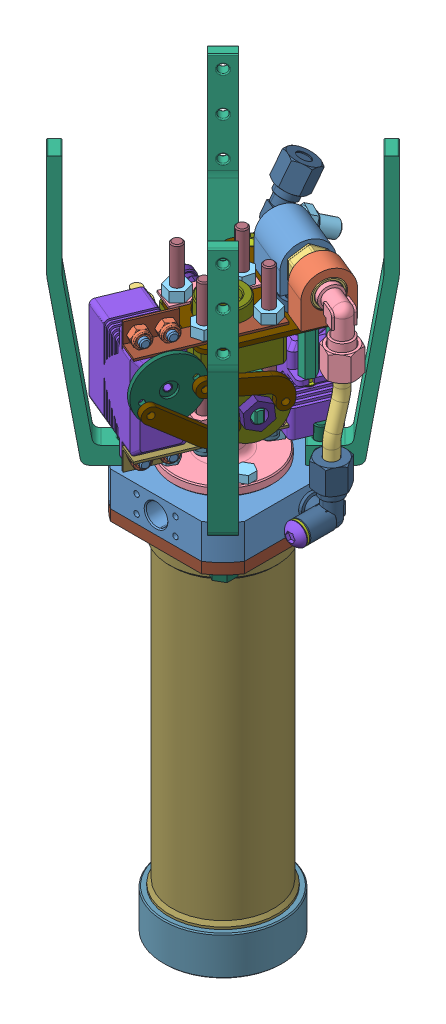
SolidWorks assembly Engine_new, configuration Standard. Lengths in mm.
Overall size (102.61 315 114.21).
81 component instances, 42 part files, 150 mates.
Components (placement in the parent):
- P52_Engine_Head-1: P52_Engine_Head [Default] at origin size (62 16 62)
- P53_G-1-8_M6_Elbow-1: P53_G-1-8_M6_Elbow [Default] at (-24 8 0) x (0 1 0) z (0 0 1) size (31.91 21 12)
- P8_Pressure_Sensor-1: P8_Pressure_Sensor [Default] at (-40 34.9 0) x (0 1 0) z (-0.866025 0 0.5) size (35.2 13.2 14.52)
- P37_Injector_Lower_Ox_Valve_Flange-1: P37_Injector_Lower_Ox_Valve_Flange [Default] at (0 45 0) x (0.92388 0 0.382683) z (0.382683 0 -0.92388) size (46 45 46)
- Fastener_HexHead_M4_10-12: Fastener_HexHead_M4_10 [Default] at (-7.271 23.5 17.5537) x (0.5 0 -0.866025) z (-0.866025 0 -0.5) size (8.08 13.5 7)
- P36_Ox_Valve_Body-1: P36_Ox_Valve_Body [Default] at (0 45.4 0) x (-0.382683 0 0.92388) z (-0.92388 0 -0.382683) size (33 15.39 48.3)
- USIT_M6-1: USIT_M6 [Default] at (-16.1679 40 -6.697) x (-0.215584 -0.82622 0.520466) z (-0.316181 0.563348 0.763328) size (10 1 10)
- Fastener_ButtonHead_M6_5-3: Fastener_ButtonHead_M6_5 [Default] at (-16.1679 40 -6.697) x (0.382683 0 -0.92388) z (0 1 0) size (10 8.13 10)
- P62_Venturi-1: P62_Venturi [Default] at (21.2526 8 -9) x (1 0 0) z (0 0.588472 0.808518) size (10 7.9 7.9)
- P45_6mm_G1-8_Elbow_with_Fill_Nipple-1: P45_6mm_G1-8_Elbow_with_Fill_Nipple [Default] at (36.8359 25.5 -9) x (0 -1 0) z (0 0 1) size (29.13 25.94 23.27)
- Fastener_HexHead_M4_10-13: Fastener_HexHead_M4_10 [Default] at (-17.5537 23.5 -7.271) x (0.866025 0 0.5) z (0.5 0 -0.866025) size (8.08 13.5 7)
- Fastener_HexHead_M4_10-14: Fastener_HexHead_M4_10 [Default] at (7.271 23.5 -17.5537) x (-0.5 0 0.866025) z (0.866025 0 0.5) size (8.08 13.5 7)
- Fastener_HexHead_M4_10-15: Fastener_HexHead_M4_10 [Default] at (17.5537 23.5 7.271) x (-0.866025 0 -0.5) z (-0.5 0 0.866025) size (8.08 13.5 7)
- USIT_M6-2: USIT_M6 [Default] at (40.6506 8.602 5.5) x (1 0 0) z (0 -1 0) size (10 1 10)
- Fastener_ButtonHead_M6_5-2: Fastener_ButtonHead_M6_5 [Default] at (40.6506 8.602 6.5) x (0.866025 -0.5 0) z (-0.5 -0.866025 0) size (10 8.13 10)
- P76ChamberCasing_Flange-1: P76ChamberCasing_Flange [Default] at (0 -5 0) size (62 5 62)
- P74_ChamberCasing_Tube-1: P74_ChamberCasing_Tube [Default] at (0 -170 0) x (0.700468 0 0.713684) z (-0.713684 0 0.700468) size (50 165 50)
- P77_Chamber_Liner-1: P77_Chamber_Liner [Default] at (0 -175 0) x (0.907131 0 0.420848) z (-0.420848 0 0.907131) size (44 170 44)
- P75_ChamberCasing_Retainer-1: P75_ChamberCasing_Retainer [Default] at (0 -174 0) x (-0.824424 0 -0.565973) z (0.565973 0 -0.824424) size (55 18 55)
- Fastener_HexHead_M5_35-1: Fastener_HexHead_M5_35 [Default] at (22.6274 -8.5 -22.6274) size (10.16 38.5 8.8)
- Fastener_HexHead_M5_35-2: Fastener_HexHead_M5_35 [Default] at (22.6274 -8.5 22.6274) x (0 0 1) z (-1 0 0) size (10.16 38.5 8.8)
- Fastener_HexHead_M5_35-3: Fastener_HexHead_M5_35 [Default] at (-22.6274 -8.5 22.6274) x (-1 0 0) z (0 0 -1) size (10.16 38.5 8.8)
- Fastener_HexHead_M5_35-4: Fastener_HexHead_M5_35 [Default] at (-22.6274 -8.5 -22.6274) x (0 0 -1) z (1 0 0) size (10.16 38.5 8.8)
- P40_Upper_Ox_Valve_Flange-1: P40_Upper_Ox_Valve_Flange [Default] at (0 60.1 0) x (0.382683 0 -0.92388) z (0.92388 0 0.382683) size (33 21.2 33)
- P73_Fill_Nipple_8mm-1: P73_Fill_Nipple_8mm [Default] at (-33.7216 66.7 -13.9679) x (-0.92388 0 -0.382683) z (-0.285627 -0.665521 0.689564) size (28 12 13.86)
- P28_Fuel_Valve_Plate-1: P28_Fuel_Valve_Plate [Default] at (0 73.3 0) x (-0.382683 0 0.92388) z (-0.92388 0 -0.382683) size (54.05 2 56)
- P46_Fuel_Valve_Holder_Large-1: P46_Fuel_Valve_Holder_Large [Standard] at (-5.7135 87.8 -33.2427) x (0.92388 0 0.382683) z (-0.382683 0 0.92388) size (22 22.5 20)
- P47_Fuel_Valve_Holder_Small-1: P47_Fuel_Valve_Holder_Small [Standard] at (31.2417 87.8 -17.9354) x (-0.92388 0 -0.382683) z (0.382683 0 -0.92388) size (11 22.5 20)
- P43_Fuel_Valve-1: P43_Fuel_Valve [Default] at (9.4425 86.9775 -26.9649) x (0.92388 0 0.382683) z (0.382683 0 -0.92388) size (36.01 20.82 21.82)
- P44_6mm_G1-8_Elbow_Comp_Ring_Fitting-1: P44_6mm_G1-8_Elbow_Comp_Ring_Fitting [Default] at (37.3239 70.3 -15.4161) x (0 1 0) z (0.382683 0 -0.92388) size (29.13 25.94 17.54)
- P45_6mm_G1-8_Elbow_with_Fill_Nipple-2: P45_6mm_G1-8_Elbow_with_Fill_Nipple [Default] at (-5.1644 103.5289 -41.3189) x (-0.167757 -0.898794 0.405002) z (0.343954 -0.438371 -0.830377) size (29.13 25.94 23.27)
- P72_Fill_Port_Fuel-1: P72_Fill_Port_Fuel [Default] at (-8.2559 84.1765 -43.8235) x (-0.223289 0.820781 -0.525795) z (-0.912051 -0.366263 -0.184427) size (12.7 23.5 11)
- Fastener_HexSpacer_M4_20-5: Fastener_HexSpacer_M4_20 [Default] at (23.785 53.3 -15.6121) x (0.999375 0 0.03534) z (-0.03534 0 0.999375) size (6.93 20 6)
- Fastener_HexSpacer_M4_20-6: Fastener_HexSpacer_M4_20 [Default] at (27.6119 53.3 -24.8509) size (6.93 20 6)
- Fastener_HexSpacer_M4_20-7: Fastener_HexSpacer_M4_20 [Default] at (-16.7344 53.3 -43.2197) size (6.93 20 6)
- Fastener_HexSpacer_M4_20-8: Fastener_HexSpacer_M4_20 [Default] at (-20.5612 53.3 -33.9809) size (6.93 20 6)
- Fastener_ButtonHead_M4_5-17: Fastener_ButtonHead_M4_5 [Default] at (0.8193 73.3 -35.9487) x (-0.837169 0 -0.546944) z (-0.546944 0 0.837169) size (7 6.91 7)
- Fastener_ButtonHead_M4_5-14: Fastener_ButtonHead_M4_5 [Default] at (-3.0075 73.3 -26.7099) x (1 0 0) z (0 0 -1) size (7 6.91 7)
- Fastener_ButtonHead_M4_5-15: Fastener_ButtonHead_M4_5 [Default] at (-16.7344 75.3 -43.2197) size (7 6.91 7)
- Fastener_ButtonHead_M4_5-13: Fastener_ButtonHead_M4_5 [Default] at (-20.5612 75.3 -33.9809) size (7 6.91 7)
- P41_Servo-1: P41_Servo [Default] at (3.5252 51.05 -29.4159) x (-0.92388 0 -0.382683) z (0 1 0) size (54 20.2 42.6)
- P42Sub_ServoPlate20mm-1: P42Sub_ServoPlate20mm [Standard] at (12.7641 69.25 -25.5891) x (-0.058101 0 0.998311) z (0 -1 0) size (20 20 5)
- P42Sub_ServoValveConnector-1: P42Sub_ServoValveConnector [Standard] at (12.7641 69.25 -25.5891) x (0.664829 0 0.746996) z (-0.746996 0 0.664829) size (20 8 20)
- Fastener_ButtonHead_M4_5-19: Fastener_ButtonHead_M4_5 [Default] at (27.6119 51.05 -24.8509) x (-0.400507 0 0.916294) z (0.916294 0 0.400507) size (7 6.91 7)
- Fastener_ButtonHead_M4_5-16: Fastener_ButtonHead_M4_5 [Default] at (23.785 51.05 -15.6121) x (1 0 0) z (0 0 -1) size (7 6.91 7)
- Fastener_ButtonHead_M4_5-18: Fastener_ButtonHead_M4_5 [Default] at (-20.5612 51.05 -33.9809) x (1 0 0) z (0 0 -1) size (7 6.91 7)
- Fastener_ButtonHead_M4_5-20: Fastener_ButtonHead_M4_5 [Default] at (-16.7344 51.05 -43.2197) x (-0.837169 0 -0.546944) z (-0.546944 0 0.837169) size (7 6.91 7)
- P69_Struct_OxValve_Servo_Mount_mirrored-1: P69_Struct_OxValve_Servo_Mount_mirrored [Default] at (-8.695 75.3 38.0444) x (0.92388 0 0.382683) z (0.382683 0 -0.92388) size (10 10 55)
- P68_Struct_OxValve_Servo_Mount-1: P68_Struct_OxValve_Servo_Mount [Default] at (-8.695 35 38.0444) x (0.92388 0 0.382683) z (0.382683 0 -0.92388) size (10 10 55)
- Fastener_ThreadedRod_M5_70-1: Fastener_ThreadedRod_M5_70 [Default] at (6.2377 28 15.0592) size (5 70 5)
- Fastener_ThreadedRod_M5_70-2: Fastener_ThreadedRod_M5_70 [Default] at (-15.0592 28 6.2377) x (0 0 1) z (-1 0 0) size (5 70 5)
- Fastener_ThreadedRod_M5_70-3: Fastener_ThreadedRod_M5_70 [Default] at (-6.2377 28 -15.0592) x (-1 0 0) z (0 0 -1) size (5 70 5)
- Fastener_ThreadedRod_M5_70-4: Fastener_ThreadedRod_M5_70 [Default] at (15.0592 28 -6.2377) x (0 0 -1) z (1 0 0) size (5 70 5)
- Fastener_Locknut_M5-1: Fastener_Locknut_M5 [M4 NYLOC] at (6.2377 34 15.0592) x (-0.837169 0 -0.546944) z (-0.546944 0 0.837169) size (8.08 5 7)
- Fastener_Locknut_M5-5: Fastener_Locknut_M5 [M4 NYLOC] at (-15.0592 34 6.2377) x (0.546944 0 -0.837169) z (-0.837169 0 -0.546944) size (8.08 5 7)
- Fastener_Locknut_M5-6: Fastener_Locknut_M5 [M4 NYLOC] at (-6.2377 34 -15.0592) x (0.837169 0 0.546944) z (0.546944 0 -0.837169) size (8.08 5 7)
- Fastener_Locknut_M5-7: Fastener_Locknut_M5 [M4 NYLOC] at (15.0592 34 -6.2377) x (-0.546944 0 0.837169) z (0.837169 0 0.546944) size (8.08 5 7)
- P41_Servo-2: P41_Servo [Default] at (-6.9086 55.15 27.8522) x (0 -1 0) z (0.92388 0 0.382683) size (54 20.2 42.6)
- P42Sub_ServoHorn-2: P42Sub_ServoHorn [Standard] at (9.9984 65.1501 34.8553) x (-0.096226 0.96787 0.23231) z (-0.92388 0 -0.382683) size (28 28 5.54)
- P42Sub_oxValveCouplerDisc-1: P42Sub_oxValveCouplerDisc [Default] at (25.2219 52.55 10.4473) x (0 -1 0) z (0.382683 0 -0.92388) size (26 3 26)
- Fastener_Nut_SwagelokValve-1: Fastener_Nut_SwagelokValve [Standard] at (28.9174 52.55 11.978) x (0.156112 0.913008 -0.376888) z (-0.349393 0.407941 0.84351) size (11 4 12.7)
- P42Sub_oxValvePushRod-1: P42Sub_oxValvePushRod [Default] at (31.69 55.1382 2.6713) x (-0.35005 0.404077 0.845096) z (-0.154634 -0.914725 0.373318) size (38 3 12.52)
- P42Sub_oxValvePushRod-2: P42Sub_oxValvePushRod [Default] at (21.5255 49.9618 19.3712) x (-0.350607 0.400769 0.846439) z (0.153368 0.916179 -0.370262) size (38 3 12.52)
- Fastener_ButtonHead_M4_10-14: Fastener_ButtonHead_M4_10 [Default] at (-8.822 79.3 32.4715) x (0.376014 0.185879 -0.907779) z (-0.071133 0.982573 0.171729) size (7 11.91 7)
- Fastener_ButtonHead_M4_10-12: Fastener_ButtonHead_M4_10 [Default] at (-4.9952 31 23.2328) x (0.146447 0.92388 -0.353553) z (-0.353553 0.382683 0.853553) size (7 11.91 7)
- Fastener_ButtonHead_M4_10-13: Fastener_ButtonHead_M4_10 [Default] at (-4.9952 79.3 23.2328) x (0.376014 0.185879 -0.907779) z (-0.071133 0.982573 0.171729) size (7 11.91 7)
- Fastener_ButtonHead_M4_10-15: Fastener_ButtonHead_M4_10 [Default] at (-8.822 31 32.4715) x (0.376014 0.185879 -0.907779) z (-0.071133 0.982573 0.171729) size (7 11.91 7)
- Fastener_Locknut_M4-6: Fastener_Locknut_M4 [M4 NYLOC] at (-5.8194 79.3 33.7153) x (0.146447 -0.92388 -0.353553) z (-0.353553 -0.382683 0.853553) size (8.08 5 7)
- Fastener_Locknut_M4-5: Fastener_Locknut_M4 [M4 NYLOC] at (-1.9926 31 24.4765) x (0.146447 -0.92388 -0.353553) z (-0.353553 -0.382683 0.853553) size (8.08 5 7)
- Fastener_Locknut_M4-7: Fastener_Locknut_M4 [M4 NYLOC] at (-5.8194 31 33.7153) x (0.146447 -0.92388 -0.353553) z (-0.353553 -0.382683 0.853553) size (8.08 5 7)
- Fastener_Locknut_M4-8: Fastener_Locknut_M4 [M4 NYLOC] at (-1.9926 79.3 24.4765) x (0.146447 -0.92388 -0.353553) z (-0.353553 -0.382683 0.853553) size (8.08 5 7)
- P65_Fuel_injector_tube-1: P65_Fuel_injector_tube [Default] at (41.2627 31.6 -9.028) x (0.030158 0 -0.999545) z (0.999545 0 0.030158) size (10.7 32.6 6)
- P67_Struct_OxValve_Rod_plate-1: P67_Struct_OxValve_Rod_plate [Default] at (-6.0288 75.3 -2.4981) x (0.382683 0 -0.92388) z (0.92388 0 0.382683) size (33 1 10)
- Fastener_Nut_M5-1: Fastener_Nut_M5 [Default] at (-6.2377 76.3 -15.0592) x (0.967514 0 -0.252818) z (0.252818 0 0.967514) size (10.16 4.5 8.8)
- Fastener_Nut_M5-2: Fastener_Nut_M5 [Default] at (15.0592 76.3 -6.2377) x (0.252818 0 0.967514) z (-0.967514 0 0.252818) size (10.16 4.5 8.8)
- Fastener_Nut_M5-3: Fastener_Nut_M5 [Default] at (6.2377 76.3 15.0592) x (-0.967514 0 0.252818) z (-0.252818 0 -0.967514) size (10.16 4.5 8.8)
- Fastener_Nut_M5-4: Fastener_Nut_M5 [Default] at (-15.0592 76.3 6.2377) x (-0.252818 0 -0.967514) z (0.967514 0 -0.252818) size (10.16 4.5 8.8)
- P64_Thrust_Struts-1: P64_Thrust_Struts [Default] at (0 16 0) x (0.707107 0 -0.707107) z (0.707107 0 0.707107) size (30.75 124 10)
- P64_Thrust_Struts-2: P64_Thrust_Struts [Default] at (0 16 0) x (-0.707107 0 -0.707107) z (0.707107 0 -0.707107) size (30.75 124 10)
- P64_Thrust_Struts-3: P64_Thrust_Struts [Default] at (0 16 0) x (-0.707107 0 0.707107) z (-0.707107 0 -0.707107) size (30.75 124 10)
- P64_Thrust_Struts-4: P64_Thrust_Struts [Default] at (0 16 0) x (0.707107 0 0.707107) z (-0.707107 0 0.707107) size (30.75 124 10)
Mates (geometry in assembly coordinates):
- Parallel3: parallel aligned: plane of P52_Engine_Head-1 through (-31 0 -31) normal (-1 0 0); plane of P8_Pressure_Sensor-1 through (-45.7158 38.9 3.3) normal (-1 0 0)
- Konzentrisch14: concentric anti-aligned: cylinder of P52_Engine_Head-1 through (0 0 0) axis (0 -1 0) radius 7; cylinder of P37_Injector_Lower_Ox_Valve_Flange-1 through (0 45 0) axis (0 1 0) radius 6.95
- Deckungsgleich13: coincident anti-aligned: plane of P52_Engine_Head-1 through (14.5 16 0) normal (0 1 0); plane of P37_Injector_Lower_Ox_Valve_Flange-1 through (-21.2492 16 -8.8017) normal (0 -1 0)
- Konzentrisch19: concentric anti-aligned: cylinder of P37_Injector_Lower_Ox_Valve_Flange-1 through (-7.271 45.001 17.5537) axis (0 -1 0) radius 2; cylinder of Fastener_HexHead_M4_10-1 through (-7.271 10 17.5537) axis (0 1 0) radius 2
- Deckungsgleich17: coincident anti-aligned: plane of P37_Injector_Lower_Ox_Valve_Flange-1 through (-7.391 20 -3.0615) normal (0 1 0); plane of Fastener_HexHead_M4_10-1 through (-7.271 20 17.5537) normal (0 -1 0)
- Parallel7: parallel aligned: plane of P52_Engine_Head-1 through (-31 0 31) normal (0 0 1); plane of Fastener_HexHead_M4_10-1 through (-7.271 20 21.0537) normal (0 0 1)
- Konzentrisch20: concentric anti-aligned: cylinder of P52_Engine_Head-1 through (-31 8 0) axis (-1 0 0) radius 4.4; cone of P53_G-1-8_M6_Elbow-1 through (-26.4116 8 0) axis (1 0 0)
- Abstand1: distance = 6 mm anti-aligned: plane of P53_G-1-8_M6_Elbow-1 through (-25 8 0) normal (1 0 0); plane of P52_Engine_Head-1 through (-31 0 -31) normal (-1 0 0)
- Parallel8: parallel aligned: plane of P52_Engine_Head-1 through (-31 0 31) normal (0 0 1); plane of P53_G-1-8_M6_Elbow-1 through (-40 8 4) normal (0 0 1)
- Konzentrisch21: concentric aligned: cylinder of P8_Pressure_Sensor-1 through (-40 8.7136 0) axis (0 -1 0) radius 3; cylinder of P53_G-1-8_M6_Elbow-1 through (-40 34.9 0) axis (0 -1 0) radius 2.5
- Deckungsgleich20: coincident anti-aligned: plane of P8_Pressure_Sensor-1 through (-34.2842 34.9 -3.3) normal (0 -1 0); plane of P53_G-1-8_M6_Elbow-1 through (-40 34.9 0) normal (0 1 0)
- Deckungsgleich21: coincident anti-aligned: plane of P37_Injector_Lower_Ox_Valve_Flange-1 through (-3.6955 45 -1.5307) normal (0 1 0); plane of P36_Ox_Valve_Body-1 through (0 45 0) normal (0 -1 0)
- Konzentrisch24: concentric anti-aligned: cylinder of P37_Injector_Lower_Ox_Valve_Flange-1 through (0 45 0) axis (0 1 0) radius 4; cylinder of P36_Ox_Valve_Body-1 through (0 59.7 0) axis (0 -1 0) radius 3.5
- Konzentrisch26: concentric anti-aligned: cylinder of P52_Engine_Head-1 through (7.271 16 -17.5537) axis (0 1 0) radius 1.65; cylinder of P37_Injector_Lower_Ox_Valve_Flange-1 through (7.271 45.001 -17.5537) axis (0 -1 0) radius 2
- Konzentrisch27: concentric anti-aligned: cylinder of P37_Injector_Lower_Ox_Valve_Flange-1 through (-6.2377 -82.9524 -15.0592) axis (0 1 0) radius 2.5; cylinder of P36_Ox_Valve_Body-1 through (-6.2377 59.7 -15.0592) axis (0 -1 0) radius 2.7
- Konzentrisch28: concentric aligned: cylinder of P37_Injector_Lower_Ox_Valve_Flange-1 through (-15.244 40 -6.3143) axis (-0.92388 0 -0.382683) radius 2.5; cylinder of USIT_M6-1 through (-15.244 40 -6.3143) axis (-0.92388 0 -0.382683) radius 3.35
- Deckungsgleich22: coincident anti-aligned: plane of P37_Injector_Lower_Ox_Valve_Flange-1 through (-15.244 -82.9524 -6.3143) normal (-0.92388 0 -0.382683); plane of USIT_M6-1 through (-15.244 40 -6.3143) normal (0.92388 0 0.382683)
- Konzentrisch29: concentric anti-aligned: cylinder of P52_Engine_Head-1 through (31 8 -9) axis (1 0 0) radius 4.4; cylinder of P62_Venturi-1 through (-3.046 8 -9) axis (-1 0 0) radius 3.95
- Deckungsgleich26: coincident anti-aligned: circle of P52_Engine_Head-1; cone of P62_Venturi-1 through (13.2526 8 -9) axis (-1 0 0)
- Konzentrisch31: concentric anti-aligned: cylinder of P52_Engine_Head-1 through (31 8 -9) axis (1 0 0) radius 4.4; cone of P45_6mm_G1-8_Elbow_with_Fill_Nipple-1 through (25.325 8 -9) axis (-1 0 0)
- Parallel10: parallel aligned: plane of P52_Engine_Head-1 through (14.5 16 0) normal (0 1 0); plane of P45_6mm_G1-8_Elbow_with_Fill_Nipple-1 through (38.6177 32.1 0.7362) normal (0 1 0)
- Abstand2: distance = 1 mm anti-aligned: plane of P62_Venturi-1 through (23.2526 5.8979 -7.47) normal (1 0 0); plane of P45_6mm_G1-8_Elbow_with_Fill_Nipple-1 through (24.2526 3.6407 -13.4) normal (-1 0 0)
- Deckungsgleich31: coordinate: point of P52_Engine_Head-1
- Konzentrisch32: concentric aligned: cylinder of P37_Injector_Lower_Ox_Valve_Flange-1 through (-15.244 40 -6.3143) axis (-0.92388 0 -0.382683) radius 2.5; cylinder of Fastener_ButtonHead_M6_5-1 through (-11.5485 40 -4.7835) axis (-0.92388 0 -0.382683) radius 3
- Deckungsgleich32: coincident anti-aligned: plane of USIT_M6-1 through (-16.1679 40 -6.697) normal (-0.92388 0 -0.382683); plane of Fastener_ButtonHead_M6_5-1 through (-18.0813 40 -2.0776) normal (0.92388 0 0.382683)
- Parallel11: parallel aligned: plane of P37_Injector_Lower_Ox_Valve_Flange-1 through (6.3143 -82.9524 -15.244) normal (0.382683 0 -0.92388); plane of Fastener_ButtonHead_M6_5-1 through (-18.3224 38.8453 -5.4246) normal (0.382683 0 -0.92388)
- Konzentrisch33: concentric anti-aligned: cylinder of P45_6mm_G1-8_Elbow_with_Fill_Nipple-1 through (40.6506 8.602 -2.5) axis (0 0 1) radius 2.5; cylinder of USIT_M6-2 through (40.6506 8.602 6.5) axis (0 0 -1) radius 3.35
- Deckungsgleich34: coincident anti-aligned: plane of P45_6mm_G1-8_Elbow_with_Fill_Nipple-1 through (40.6506 8.602 5.5) normal (0 0 1); plane of USIT_M6-2 through (40.6506 8.602 5.5) normal (0 0 -1)
- Konzentrisch34: concentric aligned: cylinder of P45_6mm_G1-8_Elbow_with_Fill_Nipple-1 through (40.6506 8.602 -2.5) axis (0 0 1) radius 2.5; cylinder of Fastener_ButtonHead_M6_5-2 through (40.6506 8.602 1.5) axis (0 0 1) radius 3
- Deckungsgleich35: coincident anti-aligned: plane of USIT_M6-2 through (40.6506 8.602 6.5) normal (0 0 1); plane of Fastener_ButtonHead_M6_5-2 through (36.3205 11.102 6.5) normal (0 0 -1)
- Parallel13: parallel aligned: plane of P45_6mm_G1-8_Elbow_with_Fill_Nipple-1 through (38.6177 32.1 0.7362) normal (0 1 0); plane of Fastener_ButtonHead_M6_5-2 through (39.4959 6.602 8.0036) normal (0 1 0)
- Konzentrisch35: concentric anti-aligned: cylinder of P37_Injector_Lower_Ox_Valve_Flange-1 through (0 45 0) axis (0 1 0) radius 5; cylinder of ChamberCasing_Flange-1 through (0 0 0) axis (0 -1 0) radius 18
- Deckungsgleich38: coincident anti-aligned: plane of P52_Engine_Head-1 through (37.5 0 0) normal (0 -1 0); plane of ChamberCasing_Flange-1 through (0 0 0) normal (0 1 0)
- Deckungsgleich39: coincident anti-aligned: plane of ChamberCasing_Flange-1 through (0 -5 0) normal (0 -1 0); plane of ChamberCasing_Tube-1 through (15.4103 -5 15.701) normal (0 1 0)
- Konzentrisch37: concentric aligned: cylinder of ChamberCasing_Tube-1 through (0 -170 0) axis (0 -1 0) radius 23.5; cylinder of ChamberLiner-1 through (0 -175 0) axis (0 -1 0) radius 22
- Deckungsgleich40: coincident anti-aligned: plane of ChamberCasing_Flange-1 through (0 -5 0) normal (0 -1 0); plane of ChamberLiner-1 through (16.3284 -5 7.5753) normal (0 1 0)
- Konzentrisch38: concentric aligned: cylinder of ChamberCasing_Tube-1 through (0 -170 0) axis (0 -1 0) radius 23.5; cylinder of ChamberCasing_Retainer-1 through (0 -174 0) axis (0 -1 0) radius 24
- Deckungsgleich41: coincident anti-aligned: plane of ChamberLiner-1 through (19.9569 -171 9.2586) normal (0 -1 0); plane of ChamberCasing_Retainer-1 through (-20.6106 -171 -14.1493) normal (0 1 0)
- Konzentrisch41: concentric anti-aligned: cylinder of P52_Engine_Head-1 through (-22.6274 16 -22.6274) axis (0 -1 0) radius 2.5; cylinder of ChamberCasing_Flange-1 through (-22.6274 -5 -22.6274) axis (0 1 0) radius 2.75
- Konzentrisch42: concentric anti-aligned: circle of ChamberCasing_Flange-1; cylinder of ChamberCasing_Tube-1 through (0 -170 0) axis (0 -1 0) radius 23.5
- Konzentrisch43: concentric aligned: cylinder of P52_Engine_Head-1 through (22.6274 16 -22.6274) axis (0 -1 0) radius 2.5; cylinder of Fastener_HexHead_M5_35-1 through (22.6274 30 -22.6274) axis (0 -1 0) radius 2.5
- Deckungsgleich42: coincident anti-aligned: plane of ChamberCasing_Flange-1 through (0 -5 0) normal (0 -1 0); plane of Fastener_HexHead_M5_35-1 through (22.6274 -5 -22.6274) normal (0 1 0)
- Konzentrisch44: concentric aligned: cylinder of P36_Ox_Valve_Body-1 through (0 59.7 0) axis (0 -1 0) radius 3.5; cylinder of P40_Upper_Ox_Valve_Flange-1 through (0 60.1 0) axis (0 -1 0) radius 3.5
- Deckungsgleich43: coincident anti-aligned: plane of P36_Ox_Valve_Body-1 through (0 60.1 0) normal (0 1 0); plane of P40_Upper_Ox_Valve_Flange-1 through (-1.3394 60.1 3.2336) normal (0 -1 0)
- Deckungsgleich44: coincident aligned: plane of P36_Ox_Valve_Body-1 through (-10.8333 59.7 -16.9628) normal (-0.92388 0 -0.382683); plane of P40_Upper_Ox_Valve_Flange-1 through (-21.5583 81.3 8.9297) normal (-0.92388 0 -0.382683)
- Konzentrisch45: concentric aligned: cylinder of P40_Upper_Ox_Valve_Flange-1 through (-15.244 66.7 -6.3143) axis (-0.92388 0 -0.382683) radius 4.4; cylinder of FillNipple8mm-1 through (-7.853 66.7 -3.2528) axis (-0.92388 0 -0.382683) radius 5
- Abstand3: distance = 2 mm anti-aligned: plane of P40_Upper_Ox_Valve_Flange-1 through (-21.5583 81.3 8.9297) normal (-0.92388 0 -0.382683); plane of FillNipple8mm-1 through (-17.0918 66.7 -7.0796) normal (0.92388 0 0.382683)
- Konzentrisch46: concentric aligned: cylinder of P40_Upper_Ox_Valve_Flange-1 through (0 60.1 0) axis (0 -1 0) radius 6.35; cylinder of P28_Fuel_Valve_Plate-1 through (0 75.3 0) axis (0 -1 0) radius 10.5
- Konzentrisch47: concentric aligned: cylinder of P40_Upper_Ox_Valve_Flange-1 through (-6.2377 81.3 -15.0592) axis (0 -1 0) radius 2.5; cylinder of P28_Fuel_Valve_Plate-1 through (-6.2377 75.3 -15.0592) axis (0 -1 0) radius 2.5
- Deckungsgleich46: coincident anti-aligned: plane of P40_Upper_Ox_Valve_Flange-1 through (-8.419 73.3 20.3253) normal (0 1 0); plane of P28_Fuel_Valve_Plate-1 through (-21.9334 73.3 -28.055) normal (0 -1 0)
- Konzentrisch48: concentric aligned: cylinder of P28_Fuel_Valve_Plate-1 through (0.8193 75.3 -35.9487) axis (0 -1 0) radius 2.1; cylinder of P46_Fuel_Valve_Holder_Large-1 through (0.8193 81.3 -35.9487) axis (0 -1 0) radius 2.75
- Konzentrisch49: concentric aligned: cylinder of P28_Fuel_Valve_Plate-1 through (-3.0075 75.3 -26.7099) axis (0 -1 0) radius 2.1; cylinder of P46_Fuel_Valve_Holder_Large-1 through (-3.0075 81.3 -26.7099) axis (0 -1 0) radius 2.75
- Deckungsgleich47: coincident anti-aligned: plane of P28_Fuel_Valve_Plate-1 through (-21.9334 75.3 -28.055) normal (0 1 0); plane of P46_Fuel_Valve_Holder_Large-1 through (10.7851 75.3 -15.5849) normal (0 -1 0)
- Konzentrisch50: concentric aligned: cylinder of P28_Fuel_Valve_Plate-1 through (23.785 75.3 -15.6121) axis (0 -1 0) radius 2.1; cylinder of P47_Fuel_Valve_Holder_Small-1 through (23.785 81.3 -15.6121) axis (0 -1 0) radius 2.75
- Konzentrisch51: concentric aligned: cylinder of P28_Fuel_Valve_Plate-1 through (27.6119 75.3 -24.8509) axis (0 -1 0) radius 2.1; cylinder of P47_Fuel_Valve_Holder_Small-1 through (27.6119 81.3 -24.8509) axis (0 -1 0) radius 2.75
- Deckungsgleich48: coincident anti-aligned: plane of P28_Fuel_Valve_Plate-1 through (-21.9334 75.3 -28.055) normal (0 1 0); plane of P47_Fuel_Valve_Holder_Small-1 through (24.9059 75.3 -31.3837) normal (0 -1 0)
- Konzentrisch52: concentric anti-aligned: cylinder of P46_Fuel_Valve_Holder_Large-1 through (14.6119 87.8 -24.8237) axis (-0.92388 0 -0.382683) radius 6.5; cylinder of P43_Fuel_Valve-1 through (6.2046 87.8 -28.3061) axis (0.92388 0 0.382683) radius 6.5
- Konzentrisch53: concentric anti-aligned: cylinder of P46_Fuel_Valve_Holder_Large-1 through (12.7641 97.801 -25.5891) axis (0 -1 0) radius 6; cylinder of P43_Fuel_Valve-1 through (12.7641 83.3237 -25.5891) axis (0 1 0) radius 6
- Konzentrisch54: concentric aligned: cylinder of P43_Fuel_Valve-1 through (30.7613 87.8 -18.1344) axis (-0.92388 0 -0.382683) radius 4.35; cone of P44_6mm_G1-8_Elbow_Comp_Ring_Fitting-1 through (26.6892 87.8 -19.8211) axis (-0.92388 0 -0.382683)
- Abstand4: distance = 6 mm anti-aligned: plane of P44_6mm_G1-8_Elbow_Comp_Ring_Fitting-1 through (24.0146 92.1593 -16.1664) normal (-0.92388 0 -0.382683); plane of P47_Fuel_Valve_Holder_Small-1 through (31.2417 87.8 -17.9354) normal (0.92388 0 0.382683)
- Parallel14: parallel anti-aligned: plane of P45_6mm_G1-8_Elbow_with_Fill_Nipple-1 through (38.6177 32.1 0.7362) normal (0 1 0); plane of P44_6mm_G1-8_Elbow_Comp_Ring_Fitting-1 through (42.696 63.7 -23.7293) normal (0 -1 0)
- Konzentrisch55: concentric aligned: cylinder of P43_Fuel_Valve-1 through (-1.5375 87.8 -31.513) axis (0.92388 0 0.382683) radius 4.285; cone of P45_6mm_G1-8_Elbow_with_Fill_Nipple-2 through (2.5346 87.8 -29.8263) axis (0.92388 0 0.382683)
- Abstand5: distance = 6 mm anti-aligned: plane of P45_6mm_G1-8_Elbow_with_Fill_Nipple-2 through (1.2806 85.8107 -23.9967) normal (0.92388 0 0.382683); plane of P43_Fuel_Valve-1 through (0.5078 94.4 -37.8096) normal (-0.92388 0 -0.382683)
- Konzentrisch56: concentric aligned: cylinder of P45_6mm_G1-8_Elbow_with_Fill_Nipple-2 through (-11.0076 87.6835 -37.1805) axis (0.343954 -0.438371 -0.830377) radius 5; cylinder of FillPortFuel-1 through (-11.3515 88.1219 -36.3501) axis (0.343954 -0.438371 -0.830377) radius 5
- Abstand6: distance = 1.5 mm aligned: plane of FillPortFuel-1 through (-7.0521 82.6422 -46.7299) normal (0.343954 -0.438371 -0.830377); plane of P45_6mm_G1-8_Elbow_with_Fill_Nipple-2 through (-6.5362 81.9847 -47.9754) normal (0.343954 -0.438371 -0.830377)
- Winkel1: planar angle = 2.024582 rad aligned: plane of P45_6mm_G1-8_Elbow_with_Fill_Nipple-2 through (-3.9293 95.7586 -44.533) normal (0.343954 -0.438371 -0.830377); plane of P28_Fuel_Valve_Plate-1 through (-21.9334 75.3 -28.055) normal (0 1 0)
- Konzentrisch57: concentric aligned: cylinder of P28_Fuel_Valve_Plate-1 through (23.785 75.3 -15.6121) axis (0 -1 0) radius 2.1; cylinder of Fastener_HexSpacer_M4_20-1 through (23.785 73.3 -15.6121) axis (0 -1 0) radius 2
- Deckungsgleich55: coincident anti-aligned: plane of P28_Fuel_Valve_Plate-1 through (-21.9334 73.3 -28.055) normal (0 -1 0); plane of Fastener_HexSpacer_M4_20-1 through (23.785 73.3 -15.6121) normal (0 1 0)
- Konzentrisch58: concentric aligned: cylinder of P28_Fuel_Valve_Plate-1 through (27.6119 75.3 -24.8509) axis (0 -1 0) radius 2.1; cylinder of Fastener_HexSpacer_M4_20-2 through (27.6119 73.3 -24.8509) axis (0 -1 0) radius 2
- Deckungsgleich57: coincident anti-aligned: plane of P28_Fuel_Valve_Plate-1 through (-21.9334 73.3 -28.055) normal (0 -1 0); plane of Fastener_HexSpacer_M4_20-2 through (27.6119 73.3 -24.8509) normal (0 1 0)
- Konzentrisch59: concentric aligned: cylinder of P28_Fuel_Valve_Plate-1 through (-16.7344 75.3 -43.2197) axis (0 -1 0) radius 2.1; cylinder of Fastener_HexSpacer_M4_20-3 through (-16.7344 73.3 -43.2197) axis (0 -1 0) radius 2
- Deckungsgleich58: coincident anti-aligned: plane of P28_Fuel_Valve_Plate-1 through (-21.9334 73.3 -28.055) normal (0 -1 0); plane of Fastener_HexSpacer_M4_20-3 through (-16.7344 73.3 -43.2197) normal (0 1 0)
- Konzentrisch60: concentric aligned: cylinder of P28_Fuel_Valve_Plate-1 through (-20.5612 75.3 -33.9809) axis (0 -1 0) radius 2.1; cylinder of Fastener_HexSpacer_M4_20-4 through (-20.5612 73.3 -33.9809) axis (0 -1 0) radius 2
- Deckungsgleich59: coincident anti-aligned: plane of P28_Fuel_Valve_Plate-1 through (-21.9334 73.3 -28.055) normal (0 -1 0); plane of Fastener_HexSpacer_M4_20-4 through (-20.5612 73.3 -33.9809) normal (0 1 0)
- Konzentrisch61: concentric aligned: cylinder of P28_Fuel_Valve_Plate-1 through (0.8193 75.3 -35.9487) axis (0 -1 0) radius 2.1; cylinder of Fastener_ButtonHead_M4_5-1 through (0.8193 78.3 -35.9487) axis (0 -1 0) radius 2
- Deckungsgleich60: coincident anti-aligned: plane of P28_Fuel_Valve_Plate-1 through (-21.9334 73.3 -28.055) normal (0 -1 0); plane of Fastener_ButtonHead_M4_5-1 through (3.7494 73.3 -34.0344) normal (0 1 0)
- Konzentrisch62: concentric aligned: cylinder of P28_Fuel_Valve_Plate-1 through (-3.0075 75.3 -26.7099) axis (0 -1 0) radius 2.1; cylinder of Fastener_ButtonHead_M4_5-2 through (-3.0075 78.3 -26.7099) axis (0 -1 0) radius 2
- Deckungsgleich61: coincident anti-aligned: plane of P28_Fuel_Valve_Plate-1 through (-21.9334 73.3 -28.055) normal (0 -1 0); plane of Fastener_ButtonHead_M4_5-2 through (-6.5075 73.3 -26.7099) normal (0 1 0)
- Konzentrisch63: concentric anti-aligned: cylinder of P28_Fuel_Valve_Plate-1 through (-16.7344 75.3 -43.2197) axis (0 -1 0) radius 2.1; cylinder of Fastener_ButtonHead_M4_5-3 through (-16.7344 70.3 -43.2197) axis (0 1 0) radius 2
- Konzentrisch64: concentric anti-aligned: cylinder of P28_Fuel_Valve_Plate-1 through (-20.5612 75.3 -33.9809) axis (0 -1 0) radius 2.1; cylinder of Fastener_ButtonHead_M4_5-4 through (-20.5612 70.3 -33.9809) axis (0 1 0) radius 2
- Deckungsgleich62: coincident anti-aligned: plane of P28_Fuel_Valve_Plate-1 through (-21.9334 75.3 -28.055) normal (0 1 0); plane of Fastener_ButtonHead_M4_5-4 through (-24.0612 75.3 -33.9809) normal (0 -1 0)
- Deckungsgleich63: coincident anti-aligned: plane of P28_Fuel_Valve_Plate-1 through (-21.9334 75.3 -28.055) normal (0 1 0); plane of Fastener_ButtonHead_M4_5-3 through (-20.2344 75.3 -43.2197) normal (0 -1 0)
- Konzentrisch65: concentric anti-aligned: cylinder of P43_Fuel_Valve-1 through (12.7641 83.3237 -25.5891) axis (0 1 0) radius 6; cylinder of P41_Servo-1 through (12.7641 67.751 -25.5891) axis (0 -1 0) radius 1.5
- Parallel16: parallel aligned: plane of P28_Fuel_Valve_Plate-1 through (4.1978 75.3 -38.8789) normal (0.382683 0 -0.92388); plane of P41_Servo-1 through (255.0693 95.3669 63.8449) normal (0.382683 0 -0.92388)
- Deckungsgleich65: coincident anti-aligned: plane of Fastener_HexSpacer_M4_20-2 through (27.6119 53.3 -24.8509) normal (0 -1 0); plane of P41_Servo-1 through (37.6066 53.3 -41.1412) normal (0 1 0)
- Konzentrisch66: concentric anti-aligned: cylinder of P41_Servo-1 through (12.7641 67.751 -25.5891) axis (0 -1 0) radius 1.5; cylinder of P42Sub_ServoPlate20mm-1 through (12.7641 64.25 -25.5891) axis (0 1 0) radius 4
- Abstand7: distance = 0.5 mm anti-aligned: plane of P42Sub_ServoPlate20mm-1 through (12.7641 64.25 -25.5891) normal (0 -1 0); plane of P41_Servo-1 through (17.4995 63.75 -14.1566) normal (0 1 0)
- Konzentrisch67: concentric aligned: cylinder of P42Sub_ServoPlate20mm-1 through (19.7523 67.25 -25.1824) axis (0 -1 0) radius 1.25; cylinder of P42Sub_ServoValveConnector-1 through (19.7523 77.25 -25.1824) axis (0 -1 0) radius 1.5
- Konzentrisch68: concentric aligned: cylinder of P42Sub_ServoPlate20mm-1 through (13.1708 67.25 -32.5772) axis (0 -1 0) radius 1.25; cylinder of P42Sub_ServoValveConnector-1 through (13.1708 77.25 -32.5772) axis (0 -1 0) radius 1.5
- Deckungsgleich71: coincident anti-aligned: plane of P42Sub_ServoPlate20mm-1 through (12.7641 69.25 -25.5891) normal (0 1 0); plane of P42Sub_ServoValveConnector-1 through (12.7641 69.25 -25.5891) normal (0 -1 0)
- Konzentrisch69: concentric aligned: cylinder of Fastener_HexSpacer_M4_20-2 through (27.6119 73.3 -24.8509) axis (0 -1 0) radius 2; cylinder of Fastener_ButtonHead_M4_5-5 through (27.6119 56.05 -24.8509) axis (0 -1 0) radius 2
- Konzentrisch70: concentric aligned: cylinder of Fastener_HexSpacer_M4_20-1 through (23.785 73.3 -15.6121) axis (0 -1 0) radius 2; cylinder of Fastener_ButtonHead_M4_5-6 through (23.785 56.05 -15.6121) axis (0 -1 0) radius 2
- Konzentrisch71: concentric aligned: cylinder of Fastener_HexSpacer_M4_20-4 through (-20.5612 73.3 -33.9809) axis (0 -1 0) radius 2; cylinder of Fastener_ButtonHead_M4_5-7 through (-20.5612 56.05 -33.9809) axis (0 -1 0) radius 2
- Konzentrisch72: concentric aligned: cylinder of Fastener_HexSpacer_M4_20-3 through (-16.7344 73.3 -43.2197) axis (0 -1 0) radius 2; cylinder of Fastener_ButtonHead_M4_5-8 through (-16.7344 56.05 -43.2197) axis (0 -1 0) radius 2
- Deckungsgleich72: coincident anti-aligned: plane of P41_Servo-1 through (-12.2829 51.05 -61.8061) normal (0 -1 0); plane of Fastener_ButtonHead_M4_5-7 through (-24.0612 51.05 -33.9809) normal (0 1 0)
- Deckungsgleich73: coincident anti-aligned: plane of P41_Servo-1 through (-12.2829 51.05 -61.8061) normal (0 -1 0); plane of Fastener_ButtonHead_M4_5-8 through (-13.8043 51.05 -41.3054) normal (0 1 0)
- Deckungsgleich74: coincident anti-aligned: plane of P41_Servo-1 through (31.278 51.05 -43.7626) normal (0 -1 0); plane of Fastener_ButtonHead_M4_5-5 through (29.0136 51.05 -28.0579) normal (0 1 0)
- Deckungsgleich75: coincident anti-aligned: plane of P41_Servo-1 through (31.278 51.05 -43.7626) normal (0 -1 0); plane of Fastener_ButtonHead_M4_5-6 through (20.285 51.05 -15.6121) normal (0 1 0)
- Konzentrisch73: concentric anti-aligned: cylinder of P28_Fuel_Valve_Plate-1 through (6.2377 75.3 15.0592) axis (0 -1 0) radius 2.5; cylinder of Struct_OxValveServoMountAngle_Mirrored-1 through (6.2377 75.3 15.0592) axis (0 1 0) radius 2.5
- Parallel21: parallel aligned: plane of P28_Fuel_Valve_Plate-1 through (32.0727 75.3 -25.1679) normal (0.92388 0 0.382683); plane of Struct_OxValveServoMountAngle_Mirrored-1 through (21.5914 75.3 -8.9422) normal (0.92388 0 0.382683)
- Deckungsgleich77: coincident anti-aligned: plane of P28_Fuel_Valve_Plate-1 through (-21.9334 75.3 -28.055) normal (0 1 0); plane of Struct_OxValveServoMountAngle_Mirrored-1 through (12.3526 75.3 -12.769) normal (0 -1 0)
- Konzentrisch78: concentric anti-aligned: cylinder of P37_Injector_Lower_Ox_Valve_Flange-1 through (6.2377 -82.9524 15.0592) axis (0 1 0) radius 2.5; cylinder of Struct_OxValveServoMountAngle-1 through (6.2377 35 15.0592) axis (0 -1 0) radius 2.5
- Parallel22: parallel aligned: plane of P37_Injector_Lower_Ox_Valve_Flange-1 through (15.244 -82.9524 6.3143) normal (0.92388 0 0.382683); plane of Struct_OxValveServoMountAngle-1 through (21.5914 35 -8.9422) normal (0.92388 0 0.382683)
- Deckungsgleich79: coincident anti-aligned: plane of P37_Injector_Lower_Ox_Valve_Flange-1 through (-20.3253 35 -8.419) normal (0 -1 0); plane of Struct_OxValveServoMountAngle-1 through (12.3526 35 -12.769) normal (0 1 0)
- Konzentrisch79: concentric anti-aligned: cylinder of P37_Injector_Lower_Ox_Valve_Flange-1 through (6.2377 -82.9524 15.0592) axis (0 1 0) radius 2.5; cylinder of Fastener_ThreadedRod_M5_70-1 through (6.2377 98 15.0592) axis (0 -1 0) radius 2.5
- Abstand8: distance = 7 mm aligned: plane of P37_Injector_Lower_Ox_Valve_Flange-1 through (-20.3253 35 -8.419) normal (0 -1 0); plane of Fastener_ThreadedRod_M5_70-1 through (6.2377 28 15.0592) normal (0 -1 0)
- Konzentrisch80: concentric aligned: cylinder of Fastener_ThreadedRod_M5_70-1 through (6.2377 98 15.0592) axis (0 -1 0) radius 2.5; cylinder of Fastener_Locknut_M5-1 through (6.2377 34 15.0592) axis (0 -1 0) radius 1.5706
- Deckungsgleich81: coincident anti-aligned: plane of Struct_OxValveServoMountAngle-1 through (21.5914 34 -8.9422) normal (0 -1 0); plane of Fastener_Locknut_M5-1 through (2.8544 34 12.8488) normal (0 1 0)
- Deckungsgleich88: coincident anti-aligned: plane of Struct_OxValveServoMountAngle_Mirrored-1 through (12.3526 85.3 -12.769) normal (-0.92388 0 -0.382683); plane of P41_Servo-2 through (-13.9665 82.15 50.771) normal (0.92388 0 0.382683)
- Deckungsgleich90: coincident aligned: plane of Struct_OxValveServoMountAngle_Mirrored-1 through (-8.695 75.3 38.0444) normal (-0.382683 0 0.92388); plane of P41_Servo-2 through (30.1698 323.2358 54.1427) normal (-0.382683 0 0.92388)
- Deckungsgleich91: coincident anti-aligned: plane of Struct_OxValveServoMountAngle_Mirrored-1 through (12.3526 75.3 -12.769) normal (0 -1 0); plane of P41_Servo-2 through (-13.9665 75.3 50.771) normal (0 1 0)
- Konzentrisch85: concentric anti-aligned: cylinder of P41_Servo-2 through (8.5211 65.1501 34.2434) axis (-0.92388 0 -0.382683) radius 1.5; cylinder of P42Sub_ServoHorn-2 through (4.4551 65.1501 32.5592) axis (0.92388 0 0.382683) radius 4
- Abstand12: distance = 0.3 mm aligned: plane of P41_Servo-2 through (7.3309 68.2453 37.1141) normal (0.92388 0 0.382683); plane of P42Sub_ServoHorn-2 through (8.7973 65.1501 34.3578) normal (0.92388 0 0.382683)
- Konzentrisch86: concentric anti-aligned: cylinder of P36_Ox_Valve_Body-1 through (29.3794 52.55 12.1693) axis (-0.92388 0 -0.382683) radius 3.15; cylinder of P42Sub_oxValveCouplerDisc-1 through (22.4503 52.55 9.2992) axis (0.92388 0 0.382683) radius 3.5
- Deckungsgleich92: coincident anti-aligned: plane of P36_Ox_Valve_Body-1 through (28.7288 45.4 13.7399) normal (-0.382683 0 0.92388); plane of P42Sub_oxValveCouplerDisc-1 through (21.7997 55.6094 10.8698) normal (0.382683 0 -0.92388)
- Deckungsgleich93: coincident anti-aligned: plane of P36_Ox_Valve_Body-1 through (22.4503 45.4 9.2992) normal (0.92388 0 0.382683); plane of P42Sub_oxValveCouplerDisc-1 through (22.4503 52.55 9.2992) normal (-0.92388 0 -0.382683)
- Konzentrisch87: concentric anti-aligned: cylinder of P36_Ox_Valve_Body-1 through (29.3794 52.55 12.1693) axis (-0.92388 0 -0.382683) radius 3.15; cylinder of Fastener_Nut_SwagelokValve-1 through (25.2219 52.55 10.4473) axis (0.92388 0 0.382683) radius 3.25
- Deckungsgleich94: coincident anti-aligned: plane of P42Sub_oxValveCouplerDisc-1 through (25.2219 52.55 10.4473) normal (0.92388 0 0.382683); plane of Fastener_Nut_SwagelokValve-1 through (25.2219 52.55 10.4473) normal (-0.92388 0 -0.382683)
- Konzentrisch88: concentric aligned: cylinder of P42Sub_oxValveCouplerDisc-1 through (26.1467 55.1382 0.3752) axis (0.92388 0 0.382683) radius 1.5; cylinder of P42Sub_oxValvePushRod-1 through (28.9183 55.1382 1.5233) axis (0.92388 0 0.382683) radius 1.5
- Konzentrisch89: concentric anti-aligned: cylinder of P42Sub_ServoHorn-2 through (11.8545 67.6646 25.148) axis (-0.92388 0 -0.382683) radius 1.25; cylinder of P42Sub_oxValvePushRod-1 through (18.0668 67.6646 27.7212) axis (0.92388 0 0.382683) radius 1.5
- Deckungsgleich95: coincident anti-aligned: plane of P42Sub_oxValveCouplerDisc-1 through (25.2219 52.55 10.4473) normal (0.92388 0 0.382683); plane of P42Sub_oxValvePushRod-1 through (18.0668 67.6646 27.7212) normal (-0.92388 0 -0.382683)
- Konzentrisch90: concentric anti-aligned: cylinder of P42Sub_oxValveCouplerDisc-1 through (18.7538 49.9618 18.2232) axis (0.92388 0 0.382683) radius 1.5; cylinder of P42Sub_oxValvePushRod-2 through (24.2971 49.9618 20.5193) axis (-0.92388 0 -0.382683) radius 1.5
- Deckungsgleich96: coincident anti-aligned: plane of P42Sub_oxValveCouplerDisc-1 through (25.2219 52.55 10.4473) normal (0.92388 0 0.382683); plane of P42Sub_oxValvePushRod-2 through (10.6567 62.3856 45.6109) normal (-0.92388 0 -0.382683)
- Tangential6: tangent aligned: cylinder of P42Sub_ServoHorn-2 through (4.4467 62.6356 43.0319) axis (-0.92388 0 -0.382683) radius 1.25; cylinder of P42Sub_oxValvePushRod-2 through (13.4283 62.3856 46.7589) axis (-0.92388 0 -0.382683) radius 1.5
- Konzentrisch102: concentric aligned: cylinder of Struct_OxValveServoMountAngle_Mirrored-1 through (2.4955 79.3 37.1594) axis (-0.92388 0 -0.382683) radius 2.25; cylinder of Fastener_ButtonHead_M4_10-1 through (0.4168 79.3 36.2984) axis (-0.92388 0 -0.382683) radius 2
- Konzentrisch103: concentric aligned: cylinder of Struct_OxValveServoMountAngle_Mirrored-1 through (6.3223 79.3 27.9206) axis (-0.92388 0 -0.382683) radius 2.25; cylinder of Fastener_ButtonHead_M4_10-3 through (4.2436 79.3 27.0596) axis (-0.92388 0 -0.382683) radius 2
- Konzentrisch104: concentric aligned: cylinder of Struct_OxValveServoMountAngle-1 through (2.4955 31 37.1594) axis (-0.92388 0 -0.382683) radius 2.25; cylinder of Fastener_ButtonHead_M4_10-4 through (0.4168 31 36.2984) axis (-0.92388 0 -0.382683) radius 2
- Konzentrisch105: concentric aligned: cylinder of Struct_OxValveServoMountAngle-1 through (6.3223 31 27.9206) axis (-0.92388 0 -0.382683) radius 2.25; cylinder of Fastener_ButtonHead_M4_10-2 through (4.2436 31 27.0596) axis (-0.92388 0 -0.382683) radius 2
- Deckungsgleich97: coincident anti-aligned: plane of P41_Servo-2 through (-16.0452 75.3 49.9099) normal (-0.92388 0 -0.382683); plane of Fastener_ButtonHead_M4_10-1 through (-10.1381 78.6494 35.6488) normal (0.92388 0 0.382683)
- Deckungsgleich98: coincident anti-aligned: plane of P41_Servo-2 through (-16.0452 75.3 49.9099) normal (-0.92388 0 -0.382683); plane of Fastener_ButtonHead_M4_10-3 through (-6.3112 78.6494 26.41) normal (0.92388 0 0.382683)
- Deckungsgleich99: coincident anti-aligned: plane of P41_Servo-2 through (-16.0452 28.15 49.9099) normal (-0.92388 0 -0.382683); plane of Fastener_ButtonHead_M4_10-4 through (-10.1381 30.3494 35.6488) normal (0.92388 0 0.382683)
- Deckungsgleich100: coincident anti-aligned: plane of P41_Servo-2 through (-16.0452 28.15 49.9099) normal (-0.92388 0 -0.382683); plane of Fastener_ButtonHead_M4_10-2 through (-5.5077 27.7664 24.4702) normal (0.92388 0 0.382683)
- Konzentrisch106: concentric anti-aligned: cylinder of Fastener_ButtonHead_M4_10-1 through (0.4168 79.3 36.2984) axis (-0.92388 0 -0.382683) radius 2; cylinder of Fastener_Locknut_M4-1 through (-5.8194 79.3 33.7153) axis (0.92388 0 0.382683) radius 1.5706
- Konzentrisch108: concentric anti-aligned: cylinder of Fastener_ButtonHead_M4_10-3 through (4.2436 79.3 27.0596) axis (-0.92388 0 -0.382683) radius 2; cylinder of Fastener_Locknut_M4-4 through (-1.9926 79.3 24.4765) axis (0.92388 0 0.382683) radius 1.5706
- Konzentrisch109: concentric anti-aligned: cylinder of Fastener_ButtonHead_M4_10-4 through (0.4168 31 36.2984) axis (-0.92388 0 -0.382683) radius 2; cylinder of Fastener_Locknut_M4-3 through (-5.8194 31 33.7153) axis (0.92388 0 0.382683) radius 1.5706
- Konzentrisch110: concentric anti-aligned: cylinder of Fastener_ButtonHead_M4_10-2 through (4.2436 31 27.0596) axis (-0.92388 0 -0.382683) radius 2; cylinder of Fastener_Locknut_M4-2 through (-1.9926 31 24.4765) axis (0.92388 0 0.382683) radius 1.5706
- Deckungsgleich102: coincident anti-aligned: plane of Struct_OxValveServoMountAngle-1 through (13.2765 34 -12.3863) normal (0.92388 0 0.382683); plane of Fastener_Locknut_M4-3 through (-5.2276 27.2662 32.2864) normal (-0.92388 0 -0.382683)
- Deckungsgleich103: coincident anti-aligned: plane of Struct_OxValveServoMountAngle-1 through (13.2765 34 -12.3863) normal (0.92388 0 0.382683); plane of Fastener_Locknut_M4-2 through (-1.4007 27.2662 23.0476) normal (-0.92388 0 -0.382683)
- Deckungsgleich104: coincident anti-aligned: plane of Struct_OxValveServoMountAngle_Mirrored-1 through (13.2765 76.3 -12.3863) normal (0.92388 0 0.382683); plane of Fastener_Locknut_M4-4 through (-1.4007 75.5662 23.0476) normal (-0.92388 0 -0.382683)
- Deckungsgleich105: coincident anti-aligned: plane of Struct_OxValveServoMountAngle_Mirrored-1 through (13.2765 76.3 -12.3863) normal (0.92388 0 0.382683); plane of Fastener_Locknut_M4-1 through (-5.2276 75.5662 32.2864) normal (-0.92388 0 -0.382683)
- Konzentrisch111: concentric aligned: cylinder of P44_6mm_G1-8_Elbow_Comp_Ring_Fitting-1 through (41.4044 63.78 -13.7259) axis (0 1 0) radius 3; cylinder of Pipe_Fuel_Injector-1 through (41.4044 58.9767 -13.7259) axis (0 1 0) radius 2
- Deckungsgleich106: coincident anti-aligned: plane of P45_6mm_G1-8_Elbow_with_Fill_Nipple-1 through (44.5488 31.6 -12.2861) normal (0 1 0); plane of Pipe_Fuel_Injector-1 through (41.2627 31.6 -9.028) normal (0 -1 0)
- Konzentrisch117: concentric aligned: cylinder of Fastener_ThreadedRod_M5_70-3 through (-6.2377 98 -15.0592) axis (0 -1 0) radius 2.5; cylinder of Struct_OxValveRodPlate-1 through (-6.2377 76.3 -15.0592) axis (0 -1 0) radius 2.5
- Parallel32: parallel aligned: plane of P28_Fuel_Valve_Plate-1 through (-12.364 75.3 -13.2672) normal (-0.92388 0 -0.382683); plane of Struct_OxValveRodPlate-1 through (-21.5818 76.3 8.9191) normal (-0.92388 0 -0.382683)
- Deckungsgleich109: coincident anti-aligned: plane of P28_Fuel_Valve_Plate-1 through (-21.9334 75.3 -28.055) normal (0 1 0); plane of Struct_OxValveRodPlate-1 through (-0.0005 75.3 -0.0011) normal (0 -1 0)
- Konzentrisch120: concentric aligned: cylinder of Fastener_ThreadedRod_M5_70-3 through (-6.2377 98 -15.0592) axis (0 -1 0) radius 2.5; cylinder of Fastener_Nut_M5-1 through (-6.2377 80.8 -15.0592) axis (0 -1 0) radius 2.5
- Deckungsgleich110: coincident anti-aligned: plane of Struct_OxValveRodPlate-1 through (-0.0005 76.3 -0.0011) normal (0 1 0); plane of Fastener_Nut_M5-1 through (-6.2377 76.3 -15.0592) normal (0 -1 0)
- Konzentrisch121: concentric anti-aligned: cylinder of Fastener_HexHead_M5_35-3 through (-22.6274 30 22.6274) axis (0 -1 0) radius 2.5; cylinder of P64_Thrust_Struts-1 through (-22.6274 14 22.6274) axis (0 1 0) radius 2.5
- Deckungsgleich111: coincident anti-aligned: plane of P52_Engine_Head-1 through (14.5 16 0) normal (0 1 0); plane of P64_Thrust_Struts-1 through (-15.5563 16 22.6274) normal (0 -1 0)
- Winkel3: planar angle = 2.356194 rad anti-aligned: plane of P52_Engine_Head-1 through (-31 0 31) normal (0 0 1); plane of P64_Thrust_Struts-1 through (3.5355 16 3.5355) normal (0.707107 0 0.707107)
